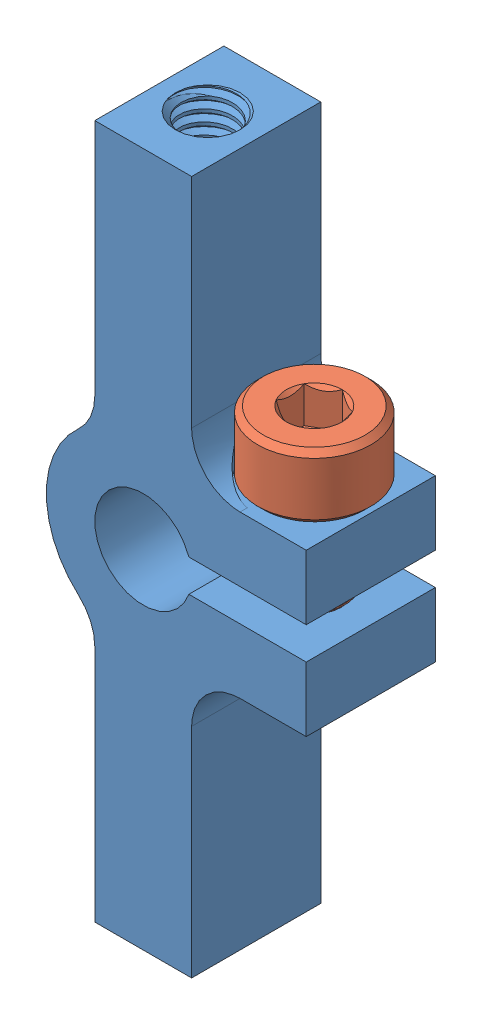
SolidWorks assembly 2-Side, 1-Post Clamping Mount (43mm Width, 6mm Bore) 1402-0043-0006, configuration Default. Lengths in mm.
Overall size (16.1 43.01 8).
2 component instances, 2 part files, 0 mates.
Components (placement in the parent):
- 1402-0043-0006 without hardware.step-1: 1402-0043-0006 without hardware.step [Default] at (-22.6062 -3.7171 7.3068) x (0 -1 0) z (1 0 0) size (43.01 8 16.1)
- 2800-0004-0010.step-1: 2800-0004-0010.step [Default] at (-16.0062 -8.7171 11.3068) size (7 14.01 7)
